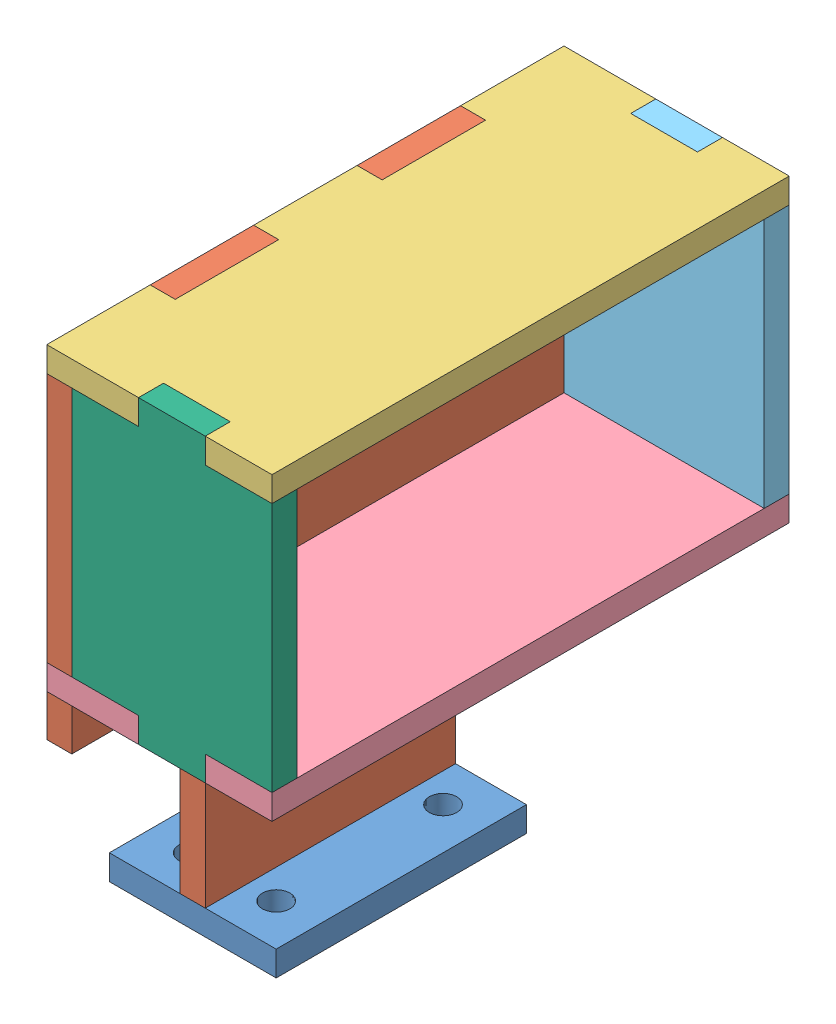
SolidWorks assembly Assem for solar panel holder, configuration Varsayılan. Lengths in mm.
Overall size (35.5 68 62).
6 component instances, 6 part files, 15 mates.
Components (placement in the parent):
- part_A1-1: part_A1 [Varsayılan] at (-0.5965 -1.2429 30) size (20 3 30)
- part_B1-3: part_B1 [Varsayılan] at (-2.0965 32.7571 30) size (3 68 62)
- Part_E1-1: Part_E1 [Varsayılan] at (11.4035 63.7571 30) x (0 0 -1) z (1 0 0) size (62 3 27)
- Part_F1-1: Part_F1 [Varsayılan] at (11.4035 30.7571 30) x (0 0 -1) z (1 0 0) size (62 3 27)
- Part_C1-1: Part_C1 [Varsayılan] at (12.9035 48.7571 2) x (0 0 -1) z (-1 0 0) size (3 36 24)
- Part_D1-1: Part_D1 [Varsayılan] at (12.9035 48.7571 61) x (0 0 -1) z (1 0 0) size (3 36 24)
Mates (geometry in assembly coordinates):
- Coincident8: coincident anti-aligned: circle of part_A1-1; plane of part_B1-3 through (0.9035 -1.2429 30) normal (0 -1 0)
- Coincident9: coincident anti-aligned: plane of part_A1-1 through (-2.0965 1.7571 39) normal (1 0 0); plane of part_B1-3 through (-2.0965 32.7571 30) normal (-1 0 0)
- Coincident10: coincident aligned: plane of part_A1-1 through (9.4035 1.7571 15) normal (0 0 -1); plane of part_B1-3 through (0.9035 32.7571 15) normal (0 0 -1)
- Coincident11: coincident anti-aligned: plane of part_B1-3 through (0.9035 32.7571 30) normal (1 0 0); plane of Part_E1-1 through (0.9035 66.7571 30) normal (-1 0 0)
- Coincident12: coincident aligned: plane of part_B1-3 through (0.9035 32.7571 61) normal (0 0 1); plane of Part_E1-1 through (11.4035 66.7571 61) normal (0 0 1)
- Coincident13: coincident anti-aligned: plane of part_B1-3 through (0.9035 63.7571 30) normal (0 1 0); plane of Part_E1-1 through (11.4035 63.7571 30) normal (0 -1 0)
- Coincident14: coincident aligned: plane of part_B1-3 through (-2.0965 32.7571 30) normal (-1 0 0); plane of Part_F1-1 through (-2.0965 33.7571 30) normal (-1 0 0)
- Coincident15: coincident aligned: plane of part_B1-3 through (0.9035 32.7571 -1) normal (0 0 -1); plane of Part_F1-1 through (11.4035 33.7571 -1) normal (0 0 -1)
- Coincident16: coincident anti-aligned: plane of part_B1-3 through (0.9035 30.7571 30) normal (0 1 0); plane of Part_F1-1 through (11.4035 30.7571 30) normal (0 -1 0)
- Coincident17: coincident aligned: plane of Part_F1-1 through (11.4035 33.7571 -1) normal (0 0 -1); plane of Part_C1-1 through (12.9035 48.7571 -1) normal (0 0 -1)
- Coincident18: coincident aligned: plane of Part_E1-1 through (11.4035 66.7571 30) normal (0 1 0); plane of Part_C1-1 through (12.9035 66.7571 -1) normal (0 1 0)
- Coincident19: coincident aligned: plane of Part_E1-1 through (24.9035 66.7571 30) normal (1 0 0); plane of Part_C1-1 through (24.9035 48.7571 -1) normal (1 0 0)
- Coincident24: coincident: plane of Part_F1-1 through (11.4035 30.7571 30) normal (0 -1 0); plane of Part_D1-1 through (13.7765 39.5702 51.9582) normal (0 -1 0)
- Coincident25: coincident: plane of Part_F1-1 through (11.4035 33.7571 61) normal (0 0 1); plane of Part_D1-1 through (13.7765 57.5702 54.9582) normal (0 0 1)
- Coincident26: coincident aligned: plane of Part_E1-1 through (24.9035 66.7571 30) normal (1 0 0); plane of Part_D1-1 through (24.9035 48.7571 58) normal (1 0 0)
